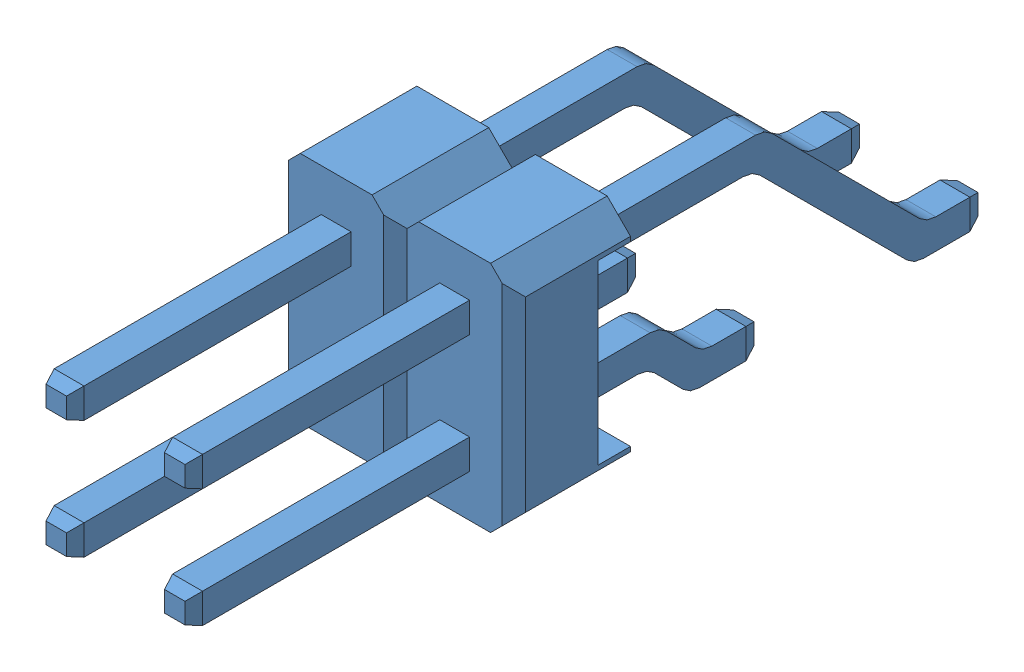
SolidWorks assembly Сборка1, configuration По умолчанию. Lengths in mm.
Overall size (5.08 5 17).
2 component instances, 1 part files, 0 mates.
Components (placement in the parent):
- 1225-122-1: 1225-122 [По умолчанию] at origin size (2.54 5 17)
- 1225-122-2: 1225-122 [По умолчанию] at (-2.54 0 0) size (2.54 5 17)
